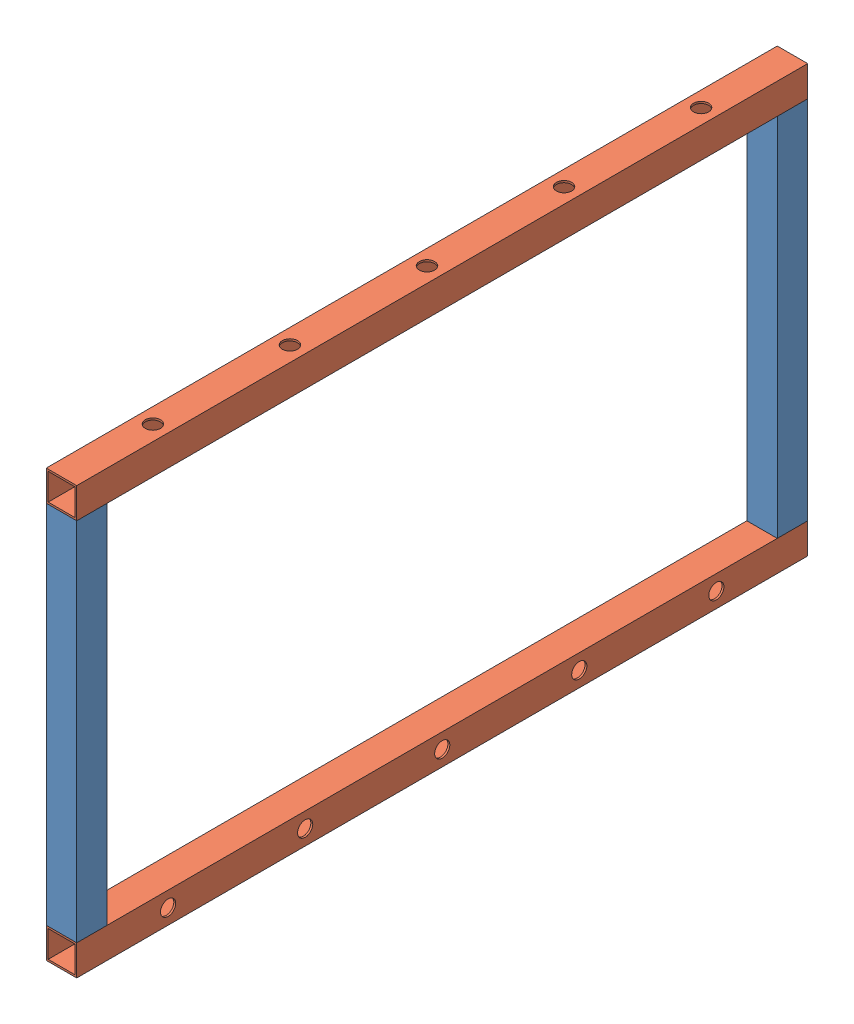
SolidWorks assembly hangDownDrilled, configuration Default. Lengths in mm.
Overall size (25.4 355.6 609.6).
4 component instances, 2 part files, 10 mates.
Components (placement in the parent):
- 12_stube-1: 12_stube [Default] at origin size (25.4 304.8 25.4)
- 24_stube-1: 24_stube [Default] at (0 -12.7 12.7) x (1 0 0) z (0 1 0) size (25.4 609.6 25.4)
- 24_stube-2: 24_stube [Default] at (0 317.5 -596.9) x (0 -1 0) z (-1 0 0) size (25.4 609.6 25.4)
- 12_stube-2: 12_stube [Default] at (0 304.8 -584.2) x (-1 0 0) z (0 0 1) size (25.4 304.8 25.4)
Mates (geometry in assembly coordinates):
- Coincident1: coincident: point of 12_stube-1; point of assembly
- Coincident2: coincident anti-aligned: plane of 12_stube-1 through (0 304.8 0) normal (0 1 0); plane of 24_stube-2 through (-12.7 304.8 12.7) normal (0 -1 0)
- Coincident4: coincident aligned: plane of 12_stube-1 through (12.7 304.8 12.7) normal (1 0 0); plane of 24_stube-2 through (12.7 330.2 12.7) normal (1 0 0)
- Coincident5: coincident aligned: plane of 12_stube-1 through (-12.7 304.8 12.7) normal (0 0 1); plane of 24_stube-2 through (0 317.5 12.7) normal (0 0 1)
- Coincident6: coincident anti-aligned: plane of 12_stube-1 through (0 0 0) normal (0 -1 0); plane of 24_stube-1 through (-12.7 0 -596.9) normal (0 1 0)
- Coincident7: coincident aligned: plane of 12_stube-1 through (-12.7 304.8 12.7) normal (0 0 1); plane of 24_stube-1 through (0 -12.7 12.7) normal (0 0 1)
- Coincident8: coincident anti-aligned: plane of 24_stube-1 through (-12.7 0 -596.9) normal (0 1 0); plane of 12_stube-2 through (0 0 -584.2) normal (0 -1 0)
- Coincident9: coincident aligned: plane of 24_stube-1 through (12.7 0 -596.9) normal (1 0 0); plane of 12_stube-2 through (12.7 0 -571.5) normal (1 0 0)
- Coincident10: coincident aligned: plane of 24_stube-1 through (0 -12.7 -596.9) normal (0 0 -1); plane of 12_stube-2 through (12.7 0 -596.9) normal (0 0 -1)
- Coincident11: coincident aligned: plane of 12_stube-1 through (-12.7 304.8 12.7) normal (-1 0 0); plane of 24_stube-1 through (-12.7 0 -596.9) normal (-1 0 0)
